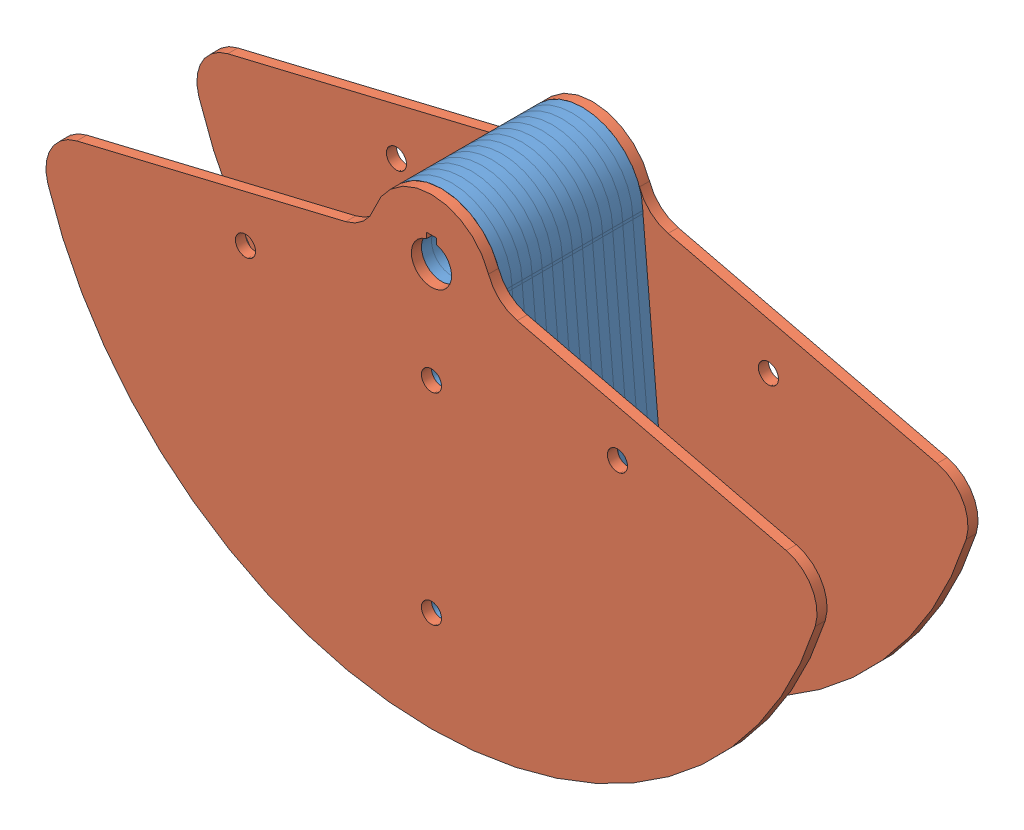
SolidWorks assembly SubAssembly_PendulumPlates, configuration Default. Lengths in mm.
Overall size (486.5 292.1 101.6).
16 component instances, 2 part files, 6 mates.
Components (placement in the parent):
- Pendulum_SemiCirc_InsidePlate-2: Pendulum_SemiCirc_InsidePlate [Default] at (0 0 3.175) size (117.55 292.1 6.35)
- Pendulum_SemiCirc_InsidePlate-3: Pendulum_SemiCirc_InsidePlate [Default] at (0 0 9.525) size (117.55 292.1 6.35)
- Pendulum_SemiCirc_InsidePlate-4: Pendulum_SemiCirc_InsidePlate [Default] at (0 0 15.875) size (117.55 292.1 6.35)
- Pendulum_SemiCirc_InsidePlate-5: Pendulum_SemiCirc_InsidePlate [Default] at (0 0 22.225) size (117.55 292.1 6.35)
- Pendulum_SemiCirc_InsidePlate-6: Pendulum_SemiCirc_InsidePlate [Default] at (0 0 28.575) size (117.55 292.1 6.35)
- Pendulum_SemiCirc_InsidePlate-7: Pendulum_SemiCirc_InsidePlate [Default] at (0 0 34.925) size (117.55 292.1 6.35)
- Pendulum_SemiCirc_InsidePlate-8: Pendulum_SemiCirc_InsidePlate [Default] at (0 0 41.275) size (117.55 292.1 6.35)
- Pendulum_SemiCirc_OutsidePlate-1: Pendulum_SemiCirc_OutsidePlate [Default] at (0 0 47.625) size (486.5 292.1 6.35)
- Pendulum_SemiCirc_InsidePlate-18: Pendulum_SemiCirc_InsidePlate [Default] at (0 0 -3.175) size (117.55 292.1 6.35)
- Pendulum_SemiCirc_InsidePlate-19: Pendulum_SemiCirc_InsidePlate [Default] at (0 0 -41.275) size (117.55 292.1 6.35)
- Pendulum_SemiCirc_OutsidePlate-3: Pendulum_SemiCirc_OutsidePlate [Default] at (0 0 -47.625) size (486.5 292.1 6.35)
- Pendulum_SemiCirc_InsidePlate-20: Pendulum_SemiCirc_InsidePlate [Default] at (0 0 -34.925) size (117.55 292.1 6.35)
- Pendulum_SemiCirc_InsidePlate-21: Pendulum_SemiCirc_InsidePlate [Default] at (0 0 -15.875) size (117.55 292.1 6.35)
- Pendulum_SemiCirc_InsidePlate-22: Pendulum_SemiCirc_InsidePlate [Default] at (0 0 -22.225) size (117.55 292.1 6.35)
- Pendulum_SemiCirc_InsidePlate-23: Pendulum_SemiCirc_InsidePlate [Default] at (0 0 -28.575) size (117.55 292.1 6.35)
- Pendulum_SemiCirc_InsidePlate-24: Pendulum_SemiCirc_InsidePlate [Default] at (0 0 -9.525) size (117.55 292.1 6.35)
Mates (geometry in assembly coordinates):
- Coincident5: coincident anti-aligned: plane of Pendulum_SemiCirc_InsidePlate-2 through (0 0 0) normal (0 0 -1); plane of assembly through (0 0 0) normal (0 0 1)
- Concentric1: concentric: cylinder of Pendulum_SemiCirc_InsidePlate-2 through (0 0 6.35) axis (0 0 -1) radius 12.7; point of assembly
- Concentric2: concentric aligned: cylinder of Pendulum_SemiCirc_OutsidePlate-1 through (0 -63.5 44.45) axis (0 0 1) radius 6.35; cylinder of Pendulum_SemiCirc_InsidePlate-8 through (0 -63.5 38.1) axis (0 0 1) radius 6.35
- Concentric3: concentric aligned: cylinder of Pendulum_SemiCirc_OutsidePlate-1 through (0 -190.5 44.45) axis (0 0 1) radius 6.35; cylinder of Pendulum_SemiCirc_InsidePlate-8 through (0 -190.5 38.1) axis (0 0 1) radius 6.35
- Coincident10: coincident anti-aligned: plane of Pendulum_SemiCirc_InsidePlate-8 through (0 0 44.45) normal (0 0 1); plane of Pendulum_SemiCirc_OutsidePlate-1 through (59.9722 20.8707 44.45) normal (0 0 -1)
- Parallel1: parallel aligned: plane of Pendulum_SemiCirc_InsidePlate-2 through (-3.175 9.525 0) normal (1 0 0); plane of assembly through (0 0 0) normal (1 0 0)
